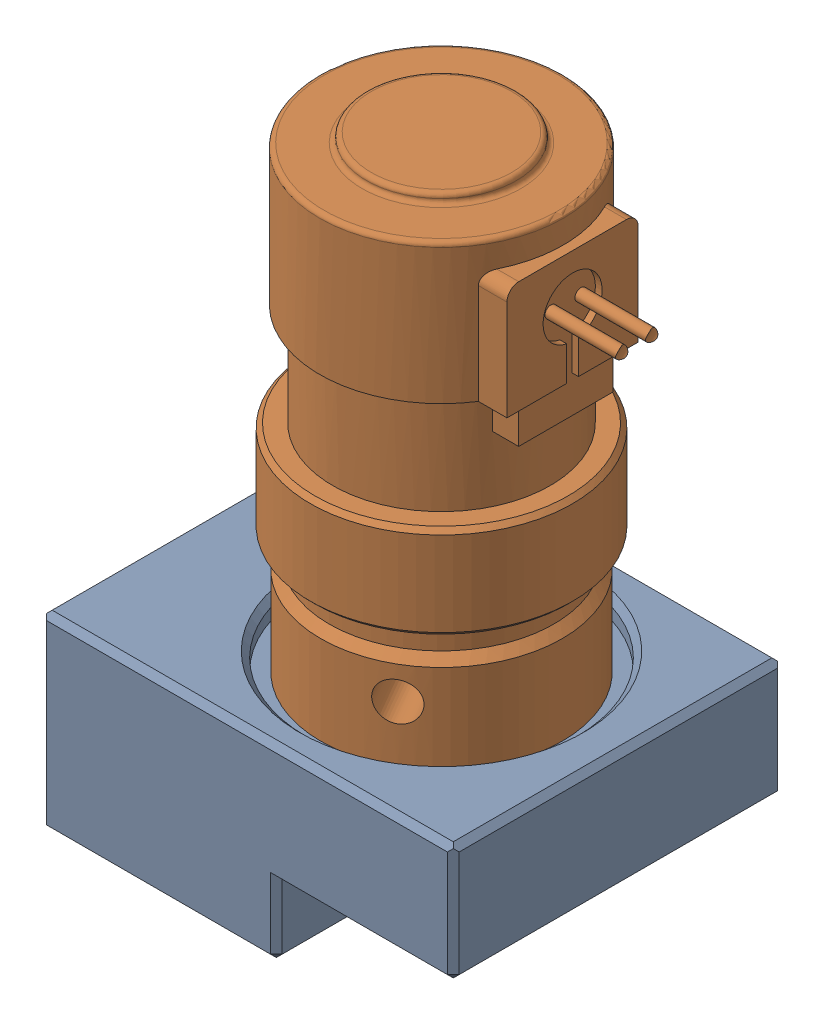
SolidWorks assembly manifold assem mockup tester, configuration Default. Lengths in mm.
Overall size (36.66 54.1 28).
2 component instances, 2 part files, 3 mates.
Components (placement in the parent):
- manifold tester-1: manifold tester [Default] at (-26.7542 -0.2678 28.2495) x (1 0 0) z (0 1 0) size (35 28 16)
- valve_cr-ev-2m-12-v-1: valve_cr-ev-2m-12-v [Default] at (-24.2542 14.2322 28.2495) size (27.77 43.6 22.23)
Mates (geometry in assembly coordinates):
- Concentric1: concentric anti-aligned: cylinder of manifold tester-1 through (-24.2542 14.2322 28.2495) axis (0 1 0) radius 11.5; cylinder of valve_cr-ev-2m-12-v-1 through (-24.2542 14.2322 28.2495) axis (0 -1 0) radius 10.2362
- Coincident3: coincident anti-aligned: plane of manifold tester-1 through (-24.2542 14.2322 28.2495) normal (0 1 0); circle of valve_cr-ev-2m-12-v-1
- Parallel1: parallel aligned: plane of manifold tester-1 through (-9.2542 15.7322 42.2495) normal (0 0 1); plane of valve_cr-ev-2m-12-v-1 through (-18.698 45.9322 33.812) normal (0 0 1)
